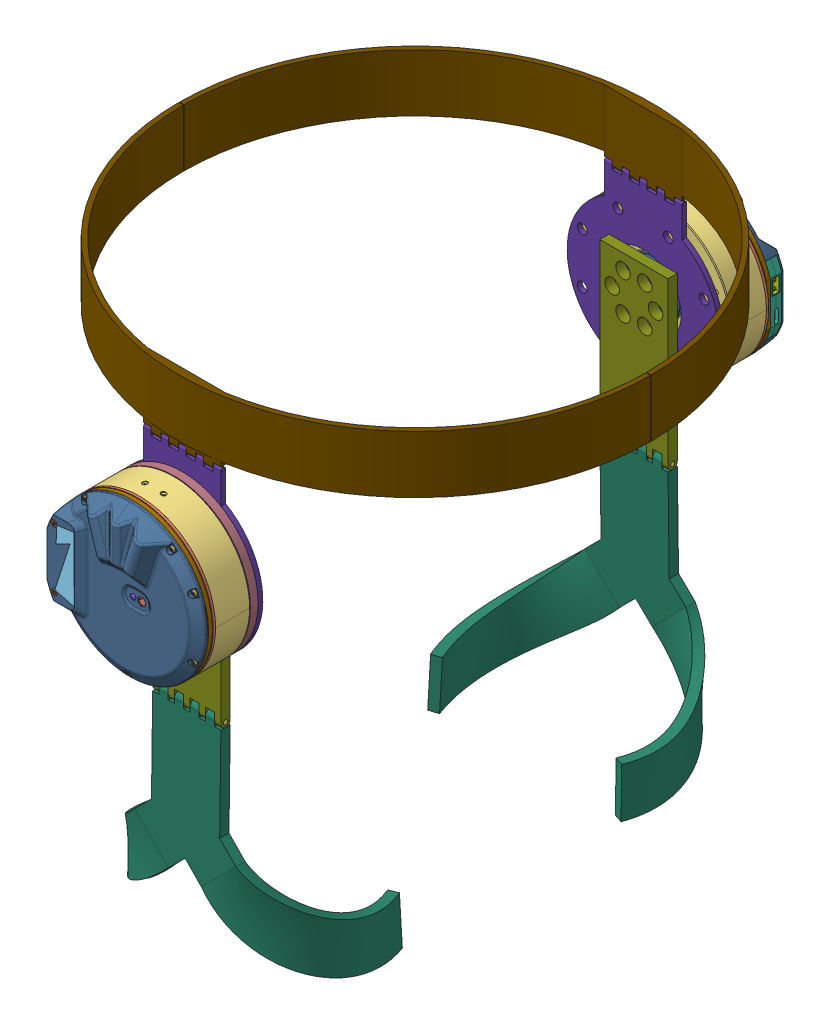
SolidWorks assembly HipExoAssem_v1, configuration Default. Lengths in mm.
Overall size (304.68 330.1 389.41).
65 component instances, 21 part files, 21 mates.
Components (placement in the parent):
- 202011-ActPack-Geared.STEP-1: 202011-ActPack-Geared.STEP [Default] at (35.2154 51.7879 75.5049) size (98 98 42.51)
  - AK80-9 3D.STEP-1: AK80-9 3D.STEP [Default] at (0 -501.6085 -756.5855) x (0 0 1) z (-1 0 0) size (28.5 98 98)
    - AK80-9 3D(2)^AK80-9 3D.STEP-1: AK80-9 3D(2)^AK80-9 3D.STEP [Default] at origin size (28.5 98 98)
      - AK80-9_ASM_ASM^AK80-9 3D(2)_AK80-9 3D.STEP-1: AK80-9_ASM_ASM^AK80-9 3D(2)_AK80-9 3D.STEP [Default] at origin size (28.5 98 98)
        - PRODUCT_46766_ASM_ASM^AK80-9_ASM_ASM_AK80-9 3D(2)_AK80-9 3D.STEP-1: PRODUCT_46766_ASM_ASM^AK80-9_ASM_ASM_AK80-9 3D(2)_AK80-9 3D.STEP [Default] at origin size (28.5 98 98)
          - ____5^PRODUCT_46766_ASM_ASM_AK80-9_ASM_ASM_AK80-9 3D(2)_AK80-9 3D.STEP-1: ____5^PRODUCT_46766_ASM_ASM_AK80-9_ASM_ASM_AK80-9 3D(2)_AK80-9 3D.STEP [Default] at origin size (7.5 37 37)
          - ____1^PRODUCT_46766_ASM_ASM_AK80-9_ASM_ASM_AK80-9 3D(2)_AK80-9 3D.STEP-1: ____1^PRODUCT_46766_ASM_ASM_AK80-9_ASM_ASM_AK80-9 3D(2)_AK80-9 3D.STEP [Default] at origin size (2 14 14) (hidden)
          - ____2^PRODUCT_46766_ASM_ASM_AK80-9-MODIFIED-20201030.STEP-1: ____2^PRODUCT_46766_ASM_ASM_AK80-9-MODIFIED-20201030.STEP [Default] at origin size (6 98 98)
          - ____7^PRODUCT_46766_ASM_ASM_AK80-9_ASM_ASM_AK80-9 3D(2)_AK80-9 3D.STEP-1: ____7^PRODUCT_46766_ASM_ASM_AK80-9_ASM_ASM_AK80-9 3D(2)_AK80-9 3D.STEP [Default] at origin size (24.23 98 98)
  - RIGID_4_1_USB_0_1.STEP-1: RIGID_4_1_USB_0_1.STEP [Default] at (-43.9 -8.8349 6.09) x (0 -1 0) z (0 0 1) size (12.35 9.94 4.02)
    - RIGID_4_1_USB_0_1(2)^RIGID_4_1_USB_0_1.STEP-1: RIGID_4_1_USB_0_1(2)^RIGID_4_1_USB_0_1.STEP [Default] at origin size (12.35 9.94 4.02)
      - J1^RIGID_4_1_USB_0_1(2)_RIGID_4_1_USB_0_1.STEP-1: J1^RIGID_4_1_USB_0_1(2)_RIGID_4_1_USB_0_1.STEP [Default] at origin size (12.35 9.94 4.02)
        - CUI_DEVICES_UJ31-CH-3-MSMT-TR-67(2)^J1_RIGID_4_1_USB_0_1(2)_RIGID_4_1_USB_0_1.STEP-1: CUI_DEVICES_UJ31-CH-3-MSMT-TR-67(2)^J1_RIGID_4_1_USB_0_1(2)_RIGID_4_1_USB_0_1.STEP [Default] at (4.6001 0.25 0.31) x (0 1 0) z (1 0 0) size (9.94 4.02 12.35)
  - APL_P003_V41_MOUNTCOVER_MB.STEP-1: APL_P003_V41_MOUNTCOVER_MB.STEP [Default] at origin size (96 98 15.01)
  - APL_P004_V41_USBMOUNT_MB.STEP-1: APL_P004_V41_USBMOUNT_MB.STEP [Default] at (-47 22.0077 2.5) x (0 -1 0) z (0 0 1) size (44.02 7.7 7.3)
  - FX_P001_V41_RIGID_LUMP.STEP-1: FX_P001_V41_RIGID_LUMP.STEP [Default] at (-39.0889 -43.5 3.51) x (1 0 0) z (0 0 1) size (13.96 13.31 8.46)
  - PLP2-100.STEP-1: PLP2-100.STEP [Default] at (5.21 0 1.7962) size (3.3 3.3 3.26)
  - APL_P001_V41_MOUNT.STEP-1: APL_P001_V41_MOUNT.STEP [Default] at origin size (96 98 2.5)
  - APL_P002_V41_COVER.STEP-1: APL_P002_V41_COVER.STEP [Default] at origin size (96 98 12.52)
  - 90236A106_ METRIC ALLOY STEEL TORX FLAT HEAD SCREWS (1)_90236A106.STEP-1: 90236A106_ METRIC ALLOY STEEL TORX FLAT HEAD SCREWS (1)_90236A106.STEP [Default] at (-42.05 19.2577 11.1) size (3.8 3.8 0.9)
  - 90236A106_ METRIC ALLOY STEEL TORX FLAT HEAD SCREWS (1)_90236A106.STEP-2: 90236A106_ METRIC ALLOY STEEL TORX FLAT HEAD SCREWS (1)_90236A106.STEP [Default] at (-42.05 -19.2577 11.1) size (3.8 3.8 0.9)
  - 90910A920_LOW-PROFILE BUTTON HEAD TORX MACHINE SCREW (1)_90910A920.STEP-1: 90910A920_LOW-PROFILE BUTTON HEAD TORX MACHINE SCREW (1)_90910A920.STEP [Default] at (0 -46.25 5.5) size (3.8 3.8 1.1)
  - 90910A920_LOW-PROFILE BUTTON HEAD TORX MACHINE SCREW (1)_90910A920.STEP-2: 90910A920_LOW-PROFILE BUTTON HEAD TORX MACHINE SCREW (1)_90910A920.STEP [Default] at (42.05 -19.2577 5.5) x (0.987351 0.158553 0) z (0 0 1) size (3.8 3.8 1.1)
  - 90910A920_LOW-PROFILE BUTTON HEAD TORX MACHINE SCREW (1)_90910A920.STEP-3: 90910A920_LOW-PROFILE BUTTON HEAD TORX MACHINE SCREW (1)_90910A920.STEP [Default] at (42.05 19.2577 5.5) x (0.959125 0.282984 0) z (0 0 1) size (3.8 3.8 1.1)
  - 90910A920_LOW-PROFILE BUTTON HEAD TORX MACHINE SCREW (1)_90910A920.STEP-4: 90910A920_LOW-PROFILE BUTTON HEAD TORX MACHINE SCREW (1)_90910A920.STEP [Default] at (28 36.8112 5.5) x (0.928571 0.371154 0) z (0 0 1) size (3.8 3.8 1.1)
  - 90910A920_LOW-PROFILE BUTTON HEAD TORX MACHINE SCREW (1)_90910A920.STEP-5: 90910A920_LOW-PROFILE BUTTON HEAD TORX MACHINE SCREW (1)_90910A920.STEP [Default] at (-28 36.8112 5.5) x (0.906989 0.421154 0) z (0 0 1) size (3.8 3.8 1.1)
- Hub_plate^HipExoAssem_v1-1: Hub_plate^HipExoAssem_v1 [Default] at (35.2154 -449.8206 51.0049) x (-1 0 0) z (0 0 -1) size (98 98 5) (virtual)
- Rotor_plate^HipExoAssem_v1-1: Rotor_plate^HipExoAssem_v1 [Default] at (35.2154 -449.8206 48.0049) x (-1 0 0) z (0 0 -1) size (44 44 5) (virtual)
- LegWrap-1: LegWrap [Default] at (35.218 -34.2108 40.0434) x (1 0 0) z (0 0.012831 0.999918) size (134.61 145.14 78.88)
- RotorConnection-2: RotorConnection [Default] at (35.218 23.7889 37.0049) size (44 108 6)
- OuterMotorAttach-1: OuterMotorAttach [Default] at (35.2154 51.7879 43.0049) size (98 112 3)
- HipAttach-1: HipAttach [Default] at (35.2154 115.7879 44.5049) size (304.68 44 152.26)
- HipAttach-3: HipAttach [Default] at (35.2148 115.7879 -252.8836) x (-1 0 0) z (0 0 -1) size (304.68 44 152.26)
- LegWrap-3: LegWrap [Default] at (35.218 -34.2108 -248.422) x (-1 0 0) z (0 0.012831 -0.999918) size (134.61 145.14 78.88)
- RotorConnection-4: RotorConnection [Default] at (35.218 23.7889 -251.3836) size (44 108 6)
- OuterMotorAttach-3: OuterMotorAttach [Default] at (35.2154 51.7879 -254.3836) size (98 112 3)
- actuator_attach (1)-2: actuator_attach (1) [Default] at (70.4307 0 -208.3786) x (-1 0 0) z (0 0 -1) size (98 98 42.51)
  - 202011-ActPack-Geared.STEP-1: 202011-ActPack-Geared.STEP [Default] at (35.2154 51.7879 75.5049) size (98 98 42.51)
    - AK80-9 3D.STEP-1: AK80-9 3D.STEP [Default] at (0 -501.6085 -756.5855) x (0 0 1) z (-1 0 0) size (28.5 98 98)
      - AK80-9 3D(2)^AK80-9 3D.STEP-1: AK80-9 3D(2)^AK80-9 3D.STEP [Default] at origin size (28.5 98 98)
        - AK80-9_ASM_ASM^AK80-9 3D(2)_AK80-9 3D.STEP-1: AK80-9_ASM_ASM^AK80-9 3D(2)_AK80-9 3D.STEP [Default] at origin size (28.5 98 98)
          - PRODUCT_46766_ASM_ASM^AK80-9_ASM_ASM_AK80-9 3D(2)_AK80-9 3D.STEP-1: PRODUCT_46766_ASM_ASM^AK80-9_ASM_ASM_AK80-9 3D(2)_AK80-9 3D.STEP [Default] at origin size (28.5 98 98)
            - ____5^PRODUCT_46766_ASM_ASM_AK80-9_ASM_ASM_AK80-9 3D(2)_AK80-9 3D.STEP-1: ____5^PRODUCT_46766_ASM_ASM_AK80-9_ASM_ASM_AK80-9 3D(2)_AK80-9 3D.STEP [Default] at origin size (7.5 37 37)
            - ____1^PRODUCT_46766_ASM_ASM_AK80-9_ASM_ASM_AK80-9 3D(2)_AK80-9 3D.STEP-1: ____1^PRODUCT_46766_ASM_ASM_AK80-9_ASM_ASM_AK80-9 3D(2)_AK80-9 3D.STEP [Default] at origin size (2 14 14) (hidden)
            - ____2^PRODUCT_46766_ASM_ASM_AK80-9-MODIFIED-20201030.STEP-1: ____2^PRODUCT_46766_ASM_ASM_AK80-9-MODIFIED-20201030.STEP [Default] at origin size (6 98 98)
            - ____7^PRODUCT_46766_ASM_ASM_AK80-9_ASM_ASM_AK80-9 3D(2)_AK80-9 3D.STEP-1: ____7^PRODUCT_46766_ASM_ASM_AK80-9_ASM_ASM_AK80-9 3D(2)_AK80-9 3D.STEP [Default] at origin size (24.23 98 98)
    - RIGID_4_1_USB_0_1.STEP-1: RIGID_4_1_USB_0_1.STEP [Default] at (-43.9 -8.8349 6.09) x (0 -1 0) z (0 0 1) size (12.35 9.94 4.02)
      - RIGID_4_1_USB_0_1(2)^RIGID_4_1_USB_0_1.STEP-1: RIGID_4_1_USB_0_1(2)^RIGID_4_1_USB_0_1.STEP [Default] at origin size (12.35 9.94 4.02)
        - J1^RIGID_4_1_USB_0_1(2)_RIGID_4_1_USB_0_1.STEP-1: J1^RIGID_4_1_USB_0_1(2)_RIGID_4_1_USB_0_1.STEP [Default] at origin size (12.35 9.94 4.02)
          - CUI_DEVICES_UJ31-CH-3-MSMT-TR-67(2)^J1_RIGID_4_1_USB_0_1(2)_RIGID_4_1_USB_0_1.STEP-1: CUI_DEVICES_UJ31-CH-3-MSMT-TR-67(2)^J1_RIGID_4_1_USB_0_1(2)_RIGID_4_1_USB_0_1.STEP [Default] at (4.6001 0.25 0.31) x (0 1 0) z (1 0 0) size (9.94 4.02 12.35)
    - APL_P003_V41_MOUNTCOVER_MB.STEP-1: APL_P003_V41_MOUNTCOVER_MB.STEP [Default] at origin size (96 98 15.01)
    - APL_P004_V41_USBMOUNT_MB.STEP-1: APL_P004_V41_USBMOUNT_MB.STEP [Default] at (-47 22.0077 2.5) x (0 -1 0) z (0 0 1) size (44.02 7.7 7.3)
    - FX_P001_V41_RIGID_LUMP.STEP-1: FX_P001_V41_RIGID_LUMP.STEP [Default] at (-39.0889 -43.5 3.51) x (1 0 0) z (0 0 1) size (13.96 13.31 8.46)
    - PLP2-100.STEP-1: PLP2-100.STEP [Default] at (5.21 0 1.7962) size (3.3 3.3 3.26)
    - APL_P001_V41_MOUNT.STEP-1: APL_P001_V41_MOUNT.STEP [Default] at origin size (96 98 2.5)
    - APL_P002_V41_COVER.STEP-1: APL_P002_V41_COVER.STEP [Default] at origin size (96 98 12.52)
    - 90236A106_ METRIC ALLOY STEEL TORX FLAT HEAD SCREWS (1)_90236A106.STEP-1: 90236A106_ METRIC ALLOY STEEL TORX FLAT HEAD SCREWS (1)_90236A106.STEP [Default] at (-42.05 19.2577 11.1) size (3.8 3.8 0.9)
    - 90236A106_ METRIC ALLOY STEEL TORX FLAT HEAD SCREWS (1)_90236A106.STEP-2: 90236A106_ METRIC ALLOY STEEL TORX FLAT HEAD SCREWS (1)_90236A106.STEP [Default] at (-42.05 -19.2577 11.1) size (3.8 3.8 0.9)
    - 90910A920_LOW-PROFILE BUTTON HEAD TORX MACHINE SCREW (1)_90910A920.STEP-1: 90910A920_LOW-PROFILE BUTTON HEAD TORX MACHINE SCREW (1)_90910A920.STEP [Default] at (0 -46.25 5.5) size (3.8 3.8 1.1)
    - 90910A920_LOW-PROFILE BUTTON HEAD TORX MACHINE SCREW (1)_90910A920.STEP-2: 90910A920_LOW-PROFILE BUTTON HEAD TORX MACHINE SCREW (1)_90910A920.STEP [Default] at (42.05 -19.2577 5.5) x (0.987351 0.158553 0) z (0 0 1) size (3.8 3.8 1.1)
    - 90910A920_LOW-PROFILE BUTTON HEAD TORX MACHINE SCREW (1)_90910A920.STEP-3: 90910A920_LOW-PROFILE BUTTON HEAD TORX MACHINE SCREW (1)_90910A920.STEP [Default] at (42.05 19.2577 5.5) x (0.959125 0.282984 0) z (0 0 1) size (3.8 3.8 1.1)
    - 90910A920_LOW-PROFILE BUTTON HEAD TORX MACHINE SCREW (1)_90910A920.STEP-4: 90910A920_LOW-PROFILE BUTTON HEAD TORX MACHINE SCREW (1)_90910A920.STEP [Default] at (28 36.8112 5.5) x (0.928571 0.371154 0) z (0 0 1) size (3.8 3.8 1.1)
    - 90910A920_LOW-PROFILE BUTTON HEAD TORX MACHINE SCREW (1)_90910A920.STEP-5: 90910A920_LOW-PROFILE BUTTON HEAD TORX MACHINE SCREW (1)_90910A920.STEP [Default] at (-28 36.8112 5.5) x (0.906989 0.421154 0) z (0 0 1) size (3.8 3.8 1.1)
  - Hub_plate^actuator_attach (1)-1: Hub_plate^actuator_attach (1) [Default] at (35.2154 -449.8206 51.0049) x (-1 0 0) z (0 0 -1) size (98 98 5) (hidden, virtual)
  - Rotor_plate^actuator_attach (1)-1: Rotor_plate^actuator_attach (1) [Default] at (35.2154 -449.8206 48.0049) x (-1 0 0) z (0 0 -1) size (44 44 5) (hidden, virtual)
Mates (geometry in assembly coordinates):
- InPlace1: in place: plane of ? through (35.2154 75.7879 51.0049) normal (0 0 -1); plane of ? through (0 0 51.0049) normal (0 0 -1); moOrthogonalPlaneRef_w of ? through (35.2154 75.7879 51.0049) normal (0 0 -1); plane of ? through (0 0 51.0049) normal (0 1 0); plane of ? through (35.2154 75.7879 51.0049) normal (0 0 -1); plane of ? through (0 0 51.0049) normal (-1 0 0); plane of ? through (35.2154 75.7879 51.0049) normal (0 0 -1); unknown of Hub_plate^HipExoAssem_v1-1
- Coincident1: coincident aligned: plane of ?; plane of ?
- Coincident2: coincident aligned: moOrthogonalPlaneRef_w of 202011-ActPack-Geared.STEP-1/AK80-9 3D.STEP-1/AK80-9 3D(2)^AK80-9 3D.STEP-1/AK80-9_ASM_ASM^AK80-9 3D(2)_AK80-9 3D.STEP-1/PRODUCT_46766_ASM_ASM^AK80-9_ASM_ASM_AK80-9 3D(2)_AK80-9 3D.STEP-1/____7^PRODUCT_46766_ASM_ASM_AK80-9_ASM_ASM_AK80-9 3D(2)_AK80-9 3D.STEP-1 through (35.2154 -449.8206 51.0049) normal (0 1 0); plane of Part14^Assem1-1 through (35.2154 -449.8206 51.0049) normal (0 1 0)
- Coincident3: coincident anti-aligned: moOrthogonalPlaneRef_w of 202011-ActPack-Geared.STEP-1/AK80-9 3D.STEP-1/AK80-9 3D(2)^AK80-9 3D.STEP-1/AK80-9_ASM_ASM^AK80-9 3D(2)_AK80-9 3D.STEP-1/PRODUCT_46766_ASM_ASM^AK80-9_ASM_ASM_AK80-9 3D(2)_AK80-9 3D.STEP-1/____7^PRODUCT_46766_ASM_ASM_AK80-9_ASM_ASM_AK80-9 3D(2)_AK80-9 3D.STEP-1 through (35.2154 -449.8206 51.0049) normal (1 0 0); plane of Part14^Assem1-1 through (35.2154 -449.8206 51.0049) normal (-1 0 0)
- InPlace2: in place: plane of ? through (35.2154 69.9879 48.0049) normal (0 0 -1); plane of ? through (0 0 48.0049) normal (0 0 -1); plane of ? through (35.2154 69.9879 48.0049) normal (0 0 -1); plane of ? through (0 0 48.0049) normal (0 1 0); plane of ? through (35.2154 69.9879 48.0049) normal (0 0 -1); plane of ? through (0 0 48.0049) normal (-1 0 0); plane of ? through (35.2154 69.9879 48.0049) normal (0 0 -1); unknown of Rotor_plate^HipExoAssem_v1-1
- Coincident4: coincident aligned: plane of ?; plane of ?
- Coincident5: coincident aligned: moOrthogonalPlaneRef_w of 202011-ActPack-Geared.STEP-1/AK80-9 3D.STEP-1/AK80-9 3D(2)^AK80-9 3D.STEP-1/AK80-9_ASM_ASM^AK80-9 3D(2)_AK80-9 3D.STEP-1/PRODUCT_46766_ASM_ASM^AK80-9_ASM_ASM_AK80-9 3D(2)_AK80-9 3D.STEP-1/____5^PRODUCT_46766_ASM_ASM_AK80-9_ASM_ASM_AK80-9 3D(2)_AK80-9 3D.STEP-1 through (35.2154 -449.8206 48.0049) normal (0 1 0); plane of Part15^Assem1-1 through (35.2154 -449.8206 48.0049) normal (0 1 0)
- Coincident6: coincident anti-aligned: moOrthogonalPlaneRef_w of 202011-ActPack-Geared.STEP-1/AK80-9 3D.STEP-1/AK80-9 3D(2)^AK80-9 3D.STEP-1/AK80-9_ASM_ASM^AK80-9 3D(2)_AK80-9 3D.STEP-1/PRODUCT_46766_ASM_ASM^AK80-9_ASM_ASM_AK80-9 3D(2)_AK80-9 3D.STEP-1/____5^PRODUCT_46766_ASM_ASM_AK80-9_ASM_ASM_AK80-9 3D(2)_AK80-9 3D.STEP-1 through (35.2154 -449.8206 48.0049) normal (1 0 0); plane of Part15^Assem1-1 through (35.2154 -449.8206 48.0049) normal (-1 0 0)
- Coincident1: coincident anti-aligned: circle of Rotor_plate^actuator_attach-1; circle of RotorConnection-2
- Coincident2: coincident anti-aligned: circle of Rotor_plate^actuator_attach-1; circle of RotorConnection-2
- Coincident3: coincident aligned: circle of LegWrap-1; circle of RotorConnection-2
- Coincident4: coincident anti-aligned: circle of LegWrap-1; circle of RotorConnection-2
- Coincident6: coincident anti-aligned: circle of OuterMotorAttach-1
- Concentric1: concentric aligned: circle of OuterMotorAttach-1; circle of HipAttach-1
- Coincident7: coincident anti-aligned: circle of OuterMotorAttach-1
- Concentric2: concentric anti-aligned: circle of OuterMotorAttach-1; circle of HipAttach-1
- Concentric3: concentric anti-aligned: circle of OuterMotorAttach-1; circle of HipAttach-1
- Concentric4: concentric aligned: circle of OuterMotorAttach-1; circle of HipAttach-1
- Coincident9: coincident anti-aligned: plane of OuterMotorAttach-1 through (15.2154 114.7879 43.0049) normal (1 0 0); plane of HipAttach-1 through (15.2154 111.7879 46.0049) normal (-1 0 0)
- Coincident10: coincident aligned: plane of OuterMotorAttach-1 through (35.2154 51.7879 43.0049) normal (0 0 -1); plane of HipAttach-1 through (10.2154 155.7879 43.0049) normal (0 0 -1)
- Coincident11: coincident aligned: circle of RotorConnection-4; circle of actuator_attach (1)-2/Rotor_plate^actuator_attach (1)-1
